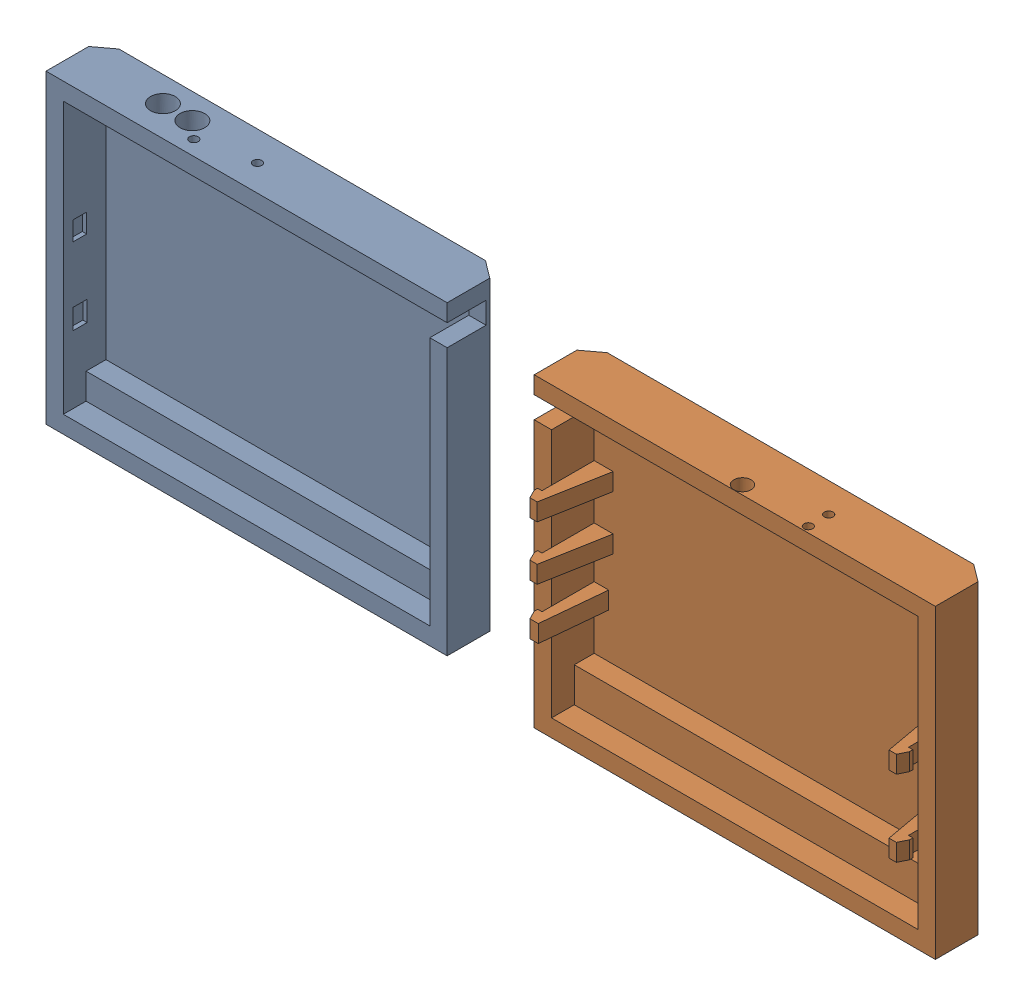
SolidWorks assembly chargerFullShell, configuration Default. Lengths in mm.
Overall size (123.21 44.98 10.71).
2 component instances, 2 part files, 1 mates.
Components (placement in the parent):
- chargerHalfShellGrooves-1: chargerHalfShellGrooves [Default] at (4.6262 -3.013 24.98) size (55.57 42.37 7.71)
- chargerHalfShellHook-1: chargerHalfShellHook [Default] at (14.2579 -5.6223 24.9849) size (55.57 42.37 10.71)
Mates (geometry in assembly coordinates):
- Coincident2: coincident aligned: plane of chargerHalfShellGrooves-1 through (30.0321 36.0981 16.4736) normal (0 0 -1); plane of chargerHalfShellHook-1 through (46.8935 33.4868 16.4736) normal (0 0 -1)
